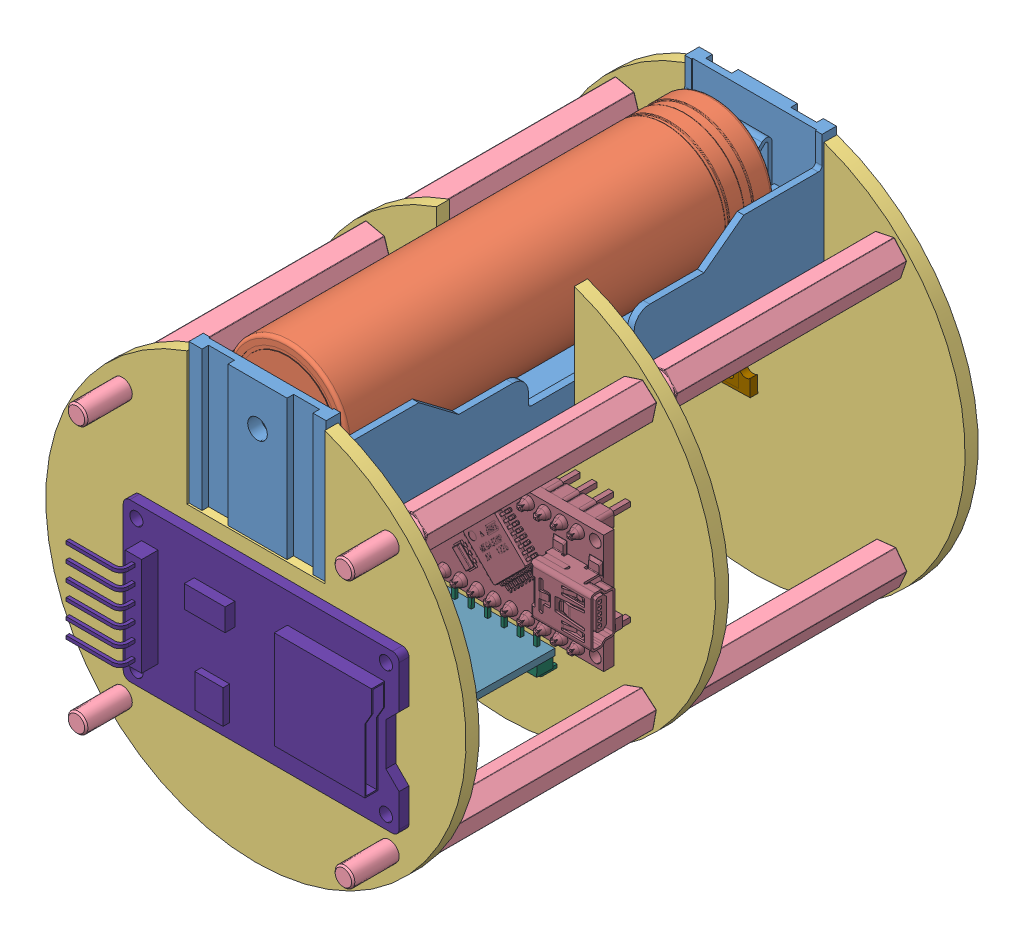
SolidWorks assembly Ensamblaje_batt, configuration Predeterminado. Lengths in mm.
Overall size (64 77.02 85).
40 component instances, 17 part files, 34 mates.
Components (placement in the parent):
- Li-Ion_Cell_Holder_BH_18650_A-1: Li-Ion_Cell_Holder_BH_18650_A [Default] at origin size (20.9 21.4 77.7)
- Samsung 30Q 18650 Battery-1: Samsung 30Q 18650 Battery [Predeterminado] at (0 15 34.3822) x (0.716861 0.697216 0) z (-0.697216 0.716861 0) size (18.4 65 18.4)
- power_pcb-1: power_pcb [Predeterminado] at (0.2535 -10.2341 -36.85) x (1 0 0) z (0 1 0) size (64 2 62.23)
- power_pcb-2: power_pcb [Predeterminado] at (0.2535 -10.2341 1.15) x (1 0 0) z (0 1 0) size (64 2 62.23)
- separador_bronce-3: separador_bronce [Predeterminado] at (20.3708 -30.3356 -1.85) x (0.404213 0.914665 0) z (0 0 1) size (5.74 5 45)
- separador_bronce-4: separador_bronce [Predeterminado] at (20.3708 10.306 -1.85) x (-0.662818 0.74878 0) z (0 0 1) size (5.74 5 45)
- separador_bronce-5: separador_bronce [Predeterminado] at (-20.2708 -30.3356 -1.85) x (-0.996255 -0.086458 0) z (0 0 1) size (5.74 5 45)
- separador_bronce-6: separador_bronce [Predeterminado] at (-20.2708 10.306 -1.85) x (-0.302153 0.95326 0) z (0 0 1) size (5.74 5 45)
- separador_bronce-8: separador_bronce [Predeterminado] at (20.3708 -30.3356 36.15) x (-0.941382 -0.337341 0) z (0 0 1) size (5.74 5 45)
- separador_bronce-9: separador_bronce [Predeterminado] at (-20.2708 10.306 36.15) x (-0.302153 0.95326 0) z (0 0 1) size (5.74 5 45)
- separador_bronce-10: separador_bronce [Predeterminado] at (-20.2708 -30.3356 36.15) x (-0.302153 0.95326 0) z (0 0 1) size (5.74 5 45)
- separador_bronce-11: separador_bronce [Predeterminado] at (20.3708 10.306 36.15) x (-0.952036 -0.305985 0) z (0 0 1) size (5.74 5 45)
- power_pcb-3: power_pcb [Predeterminado] at (-0.1535 -10.2341 37.15) x (-1 0 0) z (0 1 0) size (64 2 62.23)
- Плата ЗУ TP4056(03962A)-1: Плата ЗУ TP4056(03962A) [По умолчанию] at (-21.7808 -5.4058 -39.2679) x (0.026177 -0.999657 0) z (-0.999657 -0.026177 0) size (17.3 3.8 29.35)
  - Копия micro_usb_connector^Плата ЗУ TP4056(03962A)-1: Копия micro_usb_connector^Плата ЗУ TP4056(03962A) [По умолчанию] at (4.4684 3.5679 3.8034) x (0 0 1) z (0 1 0) size (5.84 7.77 3.44) (virtual)
    - Копия shield^Копия micro_usb_connector_Плата ЗУ TP4056(03962A)-1: Копия shield^Копия micro_usb_connector_Плата ЗУ TP4056(03962A) [По умолчанию] at origin size (5.84 7.77 3.44) (virtual)
    - Копия socket_housing^Копия micro_usb_connector_Плата ЗУ TP4056(03962A)-1: Копия socket_housing^Копия micro_usb_connector_Плата ЗУ TP4056(03962A) [По умолчанию] at origin size (4.24 6.85 2.15) (virtual)
    - Копия socket_plate^Копия micro_usb_connector_Плата ЗУ TP4056(03962A)-1: Копия socket_plate^Копия micro_usb_connector_Плата ЗУ TP4056(03962A) [По умолчанию] at origin size (3.38 6.8 0.31) (virtual)
    - Копия terminal^Копия micro_usb_connector_Плата ЗУ TP4056(03962A)-2: Копия terminal^Копия micro_usb_connector_Плата ЗУ TP4056(03962A) [По умолчанию] at (0 -1.3 0) size (3.22 0.35 1.72) (virtual)
    - Копия terminal^Копия micro_usb_connector_Плата ЗУ TP4056(03962A)-6: Копия terminal^Копия micro_usb_connector_Плата ЗУ TP4056(03962A) [По умолчанию] at (0 -0.65 0) size (3.22 0.35 1.72) (virtual)
    - Копия terminal^Копия micro_usb_connector_Плата ЗУ TP4056(03962A)-7: Копия terminal^Копия micro_usb_connector_Плата ЗУ TP4056(03962A) [По умолчанию] at origin size (3.22 0.35 1.72) (virtual)
    - Копия terminal^Копия micro_usb_connector_Плата ЗУ TP4056(03962A)-8: Копия terminal^Копия micro_usb_connector_Плата ЗУ TP4056(03962A) [По умолчанию] at (0 0.65 0) size (3.22 0.35 1.72) (virtual)
    - Копия terminal^Копия micro_usb_connector_Плата ЗУ TP4056(03962A)-9: Копия terminal^Копия micro_usb_connector_Плата ЗУ TP4056(03962A) [По умолчанию] at (0 1.3 0) size (3.22 0.35 1.72) (virtual)
  - Деталь11^Плата ЗУ TP4056(03962A)-1: Деталь11^Плата ЗУ TP4056(03962A) [По умолчанию] at (4.4684 3.5679 3.8034) x (0 0 1) z (0 1 0) size (27.9 17.3 2.06) (virtual)
  - Копия MO-153AA^Плата ЗУ TP4056(03962A)-1: Копия MO-153AA^Плата ЗУ TP4056(03962A) [По умолчанию] at (7.0684 3.5679 -14.7726) x (0 0 1) z (0 1 0) size (3.1 6.6 1.2) (virtual)
  - Копия SC-74^Плата ЗУ TP4056(03962A)-1: Копия SC-74^Плата ЗУ TP4056(03962A) [По умолчанию] at (0.7184 3.5679 -14.7726) x (0 0 -1) z (0 1 0) size (3.1 3.2 1.45) (virtual)
  - Копия MS-012AA^Плата ЗУ TP4056(03962A)-1: Копия MS-012AA^Плата ЗУ TP4056(03962A) [По умолчанию] at (4.0184 3.5679 -3.8226) x (0 0 -1) z (0 1 0) size (5 6.2 1.75) (virtual)
- User Library-arduino_nano-1: User Library-arduino_nano [Predeterminado] at (-16.8744 -19.4988 7.0396) x (1 0 0) z (0 -1 0) size (45 18.6 18)
- GY521-1: GY521 [Predeterminado] at (-0.6256 -27.341 10.9432) x (1 0 0) z (0 -0.008727 -0.999962) size (20.52 65.96 22.5)
  - Placa_GY521-1: Placa_GY521 [Predeterminado] at (0.1306 -0.272 0) size (20.27 65.96 16.25)
  - PIN_90deg-1: PIN_90deg [Predeterminado] at (-9.1926 0.728 6.9495) x (-1 0 0) z (0 0 -1) size (2.5 7.15 8.5)
  - PIN_90deg-2: PIN_90deg [Predeterminado] at (-6.6926 0.728 6.9495) x (-1 0 0) z (0 0 -1) size (2.5 7.15 8.5)
  - PIN_90deg-3: PIN_90deg [Predeterminado] at (-4.1926 0.728 6.9495) x (-1 0 0) z (0 0 -1) size (2.5 7.15 8.5)
  - PIN_90deg-4: PIN_90deg [Predeterminado] at (-1.6926 0.728 6.9495) x (-1 0 0) z (0 0 -1) size (2.5 7.15 8.5)
  - PIN_90deg-5: PIN_90deg [Predeterminado] at (0.8074 0.728 6.9495) x (-1 0 0) z (0 0 -1) size (2.5 7.15 8.5)
  - PIN_90deg-6: PIN_90deg [Predeterminado] at (3.3074 0.728 6.9495) x (-1 0 0) z (0 0 -1) size (2.5 7.15 8.5)
  - PIN_90deg-7: PIN_90deg [Predeterminado] at (5.8074 0.728 6.9495) x (-1 0 0) z (0 0 -1) size (2.5 7.15 8.5)
  - PIN_90deg-8: PIN_90deg [Predeterminado] at (8.3074 0.728 6.9495) x (-1 0 0) z (0 0 -1) size (2.5 7.15 8.5)
- GPS_pcb-1: GPS_pcb [Predeterminado] at (3.001 -17.4427 -0.85) x (0.008727 -0.999962 0) z (0.999962 0.008727 0) size (24.5 4.3 36.5)
- micro SD-1: micro SD [Predeterminado] at (2.3528 -14.2655 39.15) x (1 0 0) z (0 -1 0) size (45.95 7.75 24)
Mates (geometry in assembly coordinates):
- Coincidente1: coincident anti-aligned: plane of Li-Ion_Cell_Holder_BH_18650_A-1 through (3 12.5594 -30.6178) normal (0 0 1); plane of Samsung 30Q 18650 Battery-1 through (0 15 -30.6178) normal (0 0 -1)
- Concéntrica2: concentric anti-aligned: circle of Li-Ion_Cell_Holder_BH_18650_A-1; circle of Samsung 30Q 18650 Battery-1
- Coincidente2: coincident anti-aligned: plane of Li-Ion_Cell_Holder_BH_18650_A-1 through (0 0 0) normal (0 -1 0); plane of power_pcb-1 through (-10.45 0 -38.85) normal (0 1 0)
- Coincidente3: coincident anti-aligned: line of Li-Ion_Cell_Holder_BH_18650_A-1 through (4.5 0 -38.85) axis (-1 0 0); line of power_pcb-1 through (-10.45 0 -38.85) axis (1 0 0)
- Coincidente4: coincident aligned: line of Li-Ion_Cell_Holder_BH_18650_A-1 through (-10.45 21.3 -38.85) axis (0 -1 0); line of power_pcb-1 through (-10.45 20.2135 -38.85) axis (0 -1 0)
- Coincidente7: coincident anti-aligned: plane of power_pcb-1 through (0.05 -10.0148 -36.85) normal (0 0 1); plane of separador_bronce-4 through (22.2842 8.1445 -36.85) normal (0 0 -1)
- Coincidente9: coincident anti-aligned: plane of power_pcb-1 through (0.05 -10.0148 -36.85) normal (0 0 1); plane of separador_bronce-3 through (19.204 -32.976 -36.85) normal (0 0 -1)
- Concéntrica9: concentric aligned: circle of power_pcb-2; cylinder of separador_bronce-4 through (20.3708 10.306 8.15) axis (0 0 -1) radius 1.5
- Coincidente12: coincident anti-aligned: plane of power_pcb-1 through (0.05 -10.0148 -36.85) normal (0 0 1); plane of separador_bronce-5 through (-17.3949 -30.086 -36.85) normal (0 0 -1)
- Concéntrica11: concentric anti-aligned: circle of power_pcb-2; cylinder of separador_bronce-6 through (-20.2708 10.306 8.15) axis (0 0 -1) radius 1.5
- Concéntrica12: concentric anti-aligned: cylinder of power_pcb-1 through (-20.2708 10.306 -38.85) axis (0 0 1) radius 1.5; cylinder of separador_bronce-6 through (-20.2708 10.306 -36.85) axis (0 0 -1) radius 1.25
- Coincidente14: coincident anti-aligned: plane of power_pcb-1 through (0.05 -10.0148 -36.85) normal (0 0 1); plane of separador_bronce-6 through (-19.3986 7.5542 -36.85) normal (0 0 -1)
- Coincidente15: coincident anti-aligned: circle of power_pcb-2; circle of separador_bronce-6
- Concéntrica13: concentric anti-aligned: cylinder of power_pcb-2 through (-20.2708 -30.3356 -0.85) axis (0 0 1) radius 1.5; cylinder of separador_bronce-5 through (-20.2708 -30.3356 8.15) axis (0 0 -1) radius 1.5
- Concéntrica14: concentric anti-aligned: cylinder of power_pcb-1 through (-20.2708 -30.3356 -38.85) axis (0 0 1) radius 1.5; cylinder of separador_bronce-5 through (-20.2708 -30.3356 -36.85) axis (0 0 -1) radius 1.25
- Concéntrica15: concentric aligned: cylinder of separador_bronce-4 through (20.3708 10.306 8.15) axis (0 0 -1) radius 1.5; cylinder of separador_bronce-11 through (20.3708 10.306 1.15) axis (0 0 -1) radius 1.25
- Coincidente17: coincident anti-aligned: plane of power_pcb-2 through (0.05 -10.0148 1.15) normal (0 0 1); plane of separador_bronce-11 through (23.1191 11.1893 1.15) normal (0 0 -1)
- Concéntrica16: concentric aligned: cylinder of separador_bronce-5 through (-20.2708 -30.3356 8.15) axis (0 0 -1) radius 1.5; cylinder of separador_bronce-10 through (-20.2708 -30.3356 1.15) axis (0 0 -1) radius 1.25
- Concéntrica17: concentric aligned: cylinder of separador_bronce-6 through (-20.2708 10.306 8.15) axis (0 0 -1) radius 1.5; cylinder of separador_bronce-9 through (-20.2708 10.306 1.15) axis (0 0 -1) radius 1.25
- Coincidente18: coincident anti-aligned: plane of power_pcb-2 through (0.05 -10.0148 1.15) normal (0 0 1); plane of separador_bronce-9 through (-19.3986 7.5542 1.15) normal (0 0 -1)
- Coincidente19: coincident anti-aligned: plane of power_pcb-2 through (0.05 -10.0148 1.15) normal (0 0 1); plane of separador_bronce-10 through (-19.3986 -33.0874 1.15) normal (0 0 -1)
- Concéntrica18: concentric aligned: cylinder of separador_bronce-3 through (20.3708 -30.3356 8.15) axis (0 0 -1) radius 1.5; cylinder of separador_bronce-8 through (20.3708 -30.3356 1.15) axis (0 0 -1) radius 1.25
- Coincidente20: coincident anti-aligned: plane of power_pcb-2 through (0.05 -10.0148 1.15) normal (0 0 1); plane of separador_bronce-8 through (23.0884 -29.3618 1.15) normal (0 0 -1)
- Concéntrica20: concentric aligned: cylinder of separador_bronce-8 through (20.3708 -30.3356 46.15) axis (0 0 -1) radius 1.5; cylinder of power_pcb-3 through (20.3708 -30.3356 39.15) axis (0 0 -1) radius 1.5
- Concéntrica21: concentric aligned: cylinder of separador_bronce-10 through (-20.2708 -30.3356 46.15) axis (0 0 -1) radius 1.5; circle of power_pcb-3
- Concéntrica22: concentric anti-aligned: cylinder of power_pcb-2 through (20.3708 -30.3356 -0.85) axis (0 0 1) radius 1.5; circle of separador_bronce-3
- Coincidente24: coincident anti-aligned: circle of separador_bronce-8; circle of power_pcb-3
- Paralelo1: parallel anti-aligned: plane of power_pcb-1 through (0.05 -10.0148 -36.85) normal (0 0 1); plane of Плата ЗУ TP4056(03962A)-1/Деталь11^Плата ЗУ TP4056(03962A)-1 through (-25.4659 -9.9723 -36.85) normal (0 0 -1)
- Coincidente26: coincident anti-aligned: plane of power_pcb-1 through (0.05 -10.0148 -36.85) normal (0 0 1); plane of Плата ЗУ TP4056(03962A)-1/Деталь11^Плата ЗУ TP4056(03962A)-1 through (-25.4659 -9.9723 -36.85) normal (0 0 -1)
- Paralelo2: parallel anti-aligned: plane of power_pcb-2 through (0.05 -10.0148 1.15) normal (0 0 1); plane of User Library-arduino_nano-1 through (-20.6944 -2.8788 7.0396) normal (0 0 -1)
- Paralelo4: parallel anti-aligned: plane of power_pcb-2 through (0.05 -10.0148 -0.85) normal (0 0 -1); plane of GPS_pcb-1 through (3.001 -17.4427 -0.85) normal (0 0 1)
- Coincidente31: coincident anti-aligned: plane of power_pcb-2 through (0.05 -10.0148 -0.85) normal (0 0 -1); plane of GPS_pcb-1 through (3.001 -17.4427 -0.85) normal (0 0 1)
- Paralelo7: parallel anti-aligned: plane of power_pcb-3 through (0.05 -10.0148 39.15) normal (0 0 1); plane of micro SD-1 through (22.3528 -25.2655 39.15) normal (0 0 -1)
- Coincidente35: coincident anti-aligned: plane of power_pcb-3 through (0.05 -10.0148 39.15) normal (0 0 1); plane of micro SD-1 through (22.3528 -25.2655 39.15) normal (0 0 -1)
